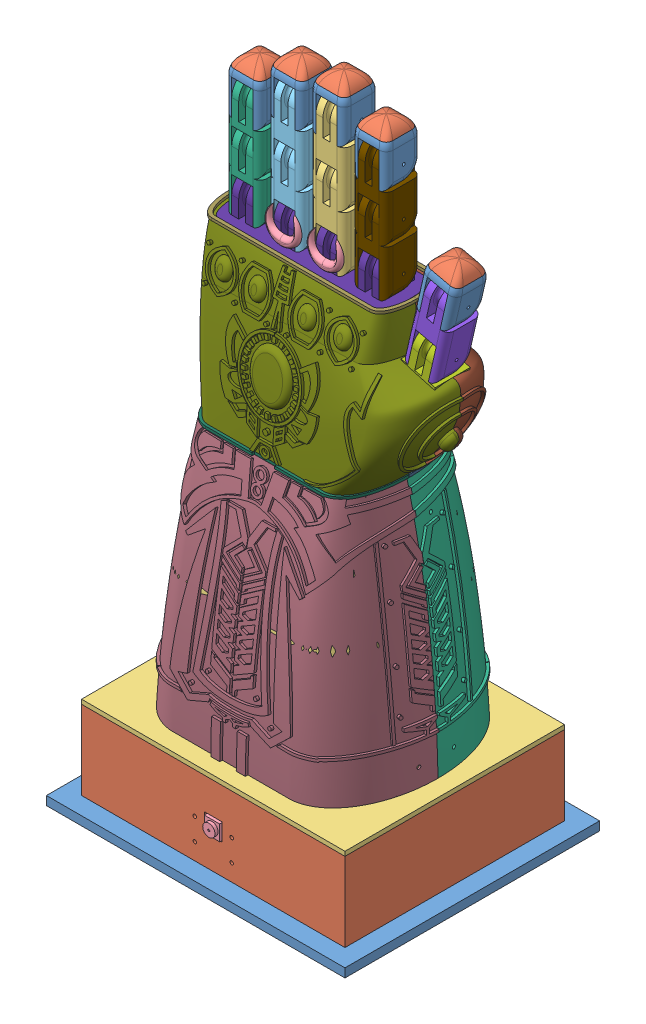
SolidWorks assembly Whole Assembly (RPi), configuration Default. Lengths in mm.
Overall size (172.28 375.5 145).
56 component instances, 26 part files, 3 mates.
Components (placement in the parent):
- Base Assembly-1: Base Assembly [Default] at (70.5365 77.5786 134.3196) size (170 72.87 145)
  - Base Bottom-2: Base Bottom [Default] at (57.5585 73.6731 141.2736) x (-1 0 0) z (0 0 -1) size (170 20 145)
  - Base Middle-1: Base Middle [Default] at (57.5585 76.1731 141.2736) size (150 47.5 125)
  - Base Top-1: Base Top [Default] at (57.5585 126.1731 141.2736) x (-1 0 0) z (0 0 -1) size (150 142.51 125)
  - Pi Camera-1: Pi Camera [Výchozí] at (57.5585 98.5731 201.2736) size (25.2 33.1 8.7)
  - Raspberry Pi 4-2: Raspberry Pi 4 [Default] at (56.6085 81.5731 132.6736) x (0 0 -1) z (1 0 0) size (89 19.92 58.4)
- Hand Assembly-1: Hand Assembly [Default] at (89.8236 183.5972 76.0301) size (158.09 323.06 115.63)
  - Back Assembly-1: Back Assembly [Default] at (44.8523 -8.137 52.37) size (148.72 230.56 93.41)
    - Arm Back-1: Arm Back [Default] at (-6.5809 28.2915 147.1931) size (139.6 140.5 63.13)
    - Servo Assembly-1: Servo Assembly [Default] at (-41.7016 175.9089 84.6263) x (1 0 0) z (0 -1 0) size (86 65.5 122.79)
      - Bed-1: Bed [Default] at (2.1207 32.6668 137.6174) size (66 39.5 122)
      - S3003-2: S3003 [Default] at (35.1207 44.6668 109.6174) x (0 0 -1) z (1 0 0) size (56.04 47.8 36.5)
      - S3003-3: S3003 [Default] at (13.1207 41.1668 109.6174) x (0 0 1) z (-1 0 0) size (56.04 47.8 36.5)
      - S3003-4: S3003 [Default] at (57.1207 41.1668 109.6174) x (0 0 1) z (-1 0 0) size (56.04 47.8 36.5)
      - S3003-5: S3003 [Default] at (13.1207 35.6668 43.6174) x (0 0 1) z (-1 0 0) size (56.04 47.8 36.5)
      - S3003-6: S3003 [Default] at (57.1207 35.6668 43.6174) x (0 0 1) z (-1 0 0) size (56.04 47.8 36.5)
      - String Holder-2: String Holder [Default] at (2.1207 60.1668 75.3674) x (1 0 0) z (0 -1 0) size (86 2.5 50)
    - Hand Bottom Decoration Back-1: Hand Bottom Decoration Back [Default] at (-6.5809 168.2915 147.1931) size (104.1 1.5 40.1)
    - Hand Back-1: Hand Back [Default] at (-6.5809 169.7915 147.1931) size (139.36 90.89 40.4)
    - Hand Top Decoration-1: Hand Top Decoration [Default] at (-6.5809 257.2915 147.1931) size (110.31 1.5 21.89)
  - Front Assembly-1: Front Assembly [Default] at (65.248 14.3274 327.8682) x (-1 0 0) z (0 0 -1) size (150.75 230.56 96.01)
    - Arm Front-1: Arm Front [Default] at (26.9766 5.8272 128.3051) size (139.6 140.48 96.01)
    - Arm Upper Lid-1: Arm Upper Lid [Default] at (26.9766 5.8272 128.3051) size (97.03 2.56 56.64)
    - Hand Bottom Decoration Front-1: Hand Bottom Decoration Front [Default] at (26.9766 145.8272 128.3051) size (104.1 1.5 40.1)
    - Hand Front-1: Hand Front [Default] at (26.9766 147.3272 128.3051) x (-1 0 0) z (0 0 -1) size (139.35 90.89 52.36)
    - Hand Top Decoration-1: Hand Top Decoration [Default] at (26.9766 234.8272 128.3051) size (110.31 1.5 21.89)
  - Finger and Lid Assembly-1: Finger and Lid Assembly [Default] at (3.2326 208.2275 112.941) size (104.96 97.49 36.85)
    - Hand Lid-1: Hand Lid [Default] at (35.0387 -46.573 86.622) size (104.96 23.49 36.85)
    - Finger Assembly 2-1: Finger Assembly 2 [Default] at (62.9609 39.05 43.1895) size (20 84 20)
      - Finger Body 2-1: Finger Body 2 [Default] at (8.0779 21.877 43.4324) size (20 47 20)
      - Finger Body 2-2: Finger Body 2 [Default] at (8.0779 48.877 43.4324) size (20 47 20)
      - Finger Top-1: Finger Top [Default] at (8.0779 75.877 43.4324) size (20 24 20)
      - Finger Tip-1: Finger Tip [Default] at (8.0779 75.877 43.4324) size (18.77 6 18.77)
    - Finger Assembly 3-1: Finger Assembly 3 [Default] at (38.9609 39.05 43.1895) size (20 94 23.03)
      - Finger Body 3-1: Finger Body 3 [Default] at (8.0779 21.877 43.4324) size (20 52 20)
      - Finger Body 3-2: Finger Body 3 [Default] at (8.0779 53.877 43.4324) size (20 52 20)
      - Finger Top-1: Finger Top [Default] at (8.0779 85.877 43.4324) size (20 24 20)
      - Finger Tip-1: Finger Tip [Default] at (8.0779 85.877 43.4324) size (18.77 6 18.77)
      - Finger Moon-1: Finger Moon [Default] at (8.0779 11.877 53.4324) x (1 0 0) z (0 -1 0) size (20 3.57 18.53)
    - Finger Assembly 4-1: Finger Assembly 4 [Default] at (14.9609 39.05 43.1895) size (20 90 23.03)
      - Finger Body 4-1: Finger Body 4 [Default] at (8.0779 21.877 43.4324) size (20 50 20)
      - Finger Body 4-2: Finger Body 4 [Default] at (8.0779 51.877 43.4324) size (20 50 20)
      - Finger Top-1: Finger Top [Default] at (8.0779 81.877 43.4324) size (20 24 20)
      - Finger Tip-1: Finger Tip [Default] at (8.0779 81.877 43.4324) size (18.77 6 18.77)
      - Finger Moon-1: Finger Moon [Default] at (8.0779 11.877 53.4324) x (1 0 0) z (0 -1 0) size (20 3.57 18.53)
    - Finger Assembly 5-1: Finger Assembly 5 [Default] at (-9.0391 39.05 43.1895) size (20 78 20)
      - Finger Body 5-1: Finger Body 5 [Default] at (8.0779 21.877 43.4324) size (20 44 20)
      - Finger Body 5-2: Finger Body 5 [Default] at (8.0779 45.877 43.4324) size (20 44 20)
      - Finger Top-1: Finger Top [Default] at (8.0779 69.877 43.4324) size (20 24 20)
      - Finger Tip-1: Finger Tip [Default] at (8.0779 69.877 43.4324) size (18.77 6 18.77)
  - Thumb and Lid Assembly-1: Thumb and Lid Assembly [Default] at (91.1371 218.4921 182.3169) x (0.974839 -0.222909 0) z (0 0 1) size (20 65 20)
    - Thumb Joint-1: Thumb Joint [Default] at (-0.2704 3.0981 27.2461) size (20 25 20)
    - Finger Assembly 1-1: Finger Assembly 1 [Default] at (1.6517 -23.7789 -26.1863) size (20 60 20)
      - Finger Body 1-2: Finger Body 1 [Default] at (8.0779 51.877 43.4324) size (20 50 20)
      - Finger Top-1: Finger Top [Default] at (8.0779 81.877 43.4324) size (20 24 20)
      - Finger Tip-1: Finger Tip [Default] at (8.0779 81.877 43.4324) size (18.77 6 18.77)
Mates (geometry in assembly coordinates):
- Coincident1: coincident anti-aligned: plane of Base Assembly-1/Base Top-1 through (128.095 203.7517 275.5932) normal (0 1 0); plane of Hand Assembly-1/Front Assembly-1/Arm Front-1 through (161.095 203.7517 275.5932) normal (0 -1 0)
- Coincident2: coincident aligned: line of Base Assembly-1/Base Top-1 through (95.095 203.7517 325.5932) axis (1 0 0); line of Hand Assembly-1/Front Assembly-1/Arm Front-1 through (95.095 203.7517 325.5932) axis (1 0 0)
- Coincident4: coincident: point of Base Assembly-1/Base Top-1; point of Hand Assembly-1/Front Assembly-1/Arm Front-1
